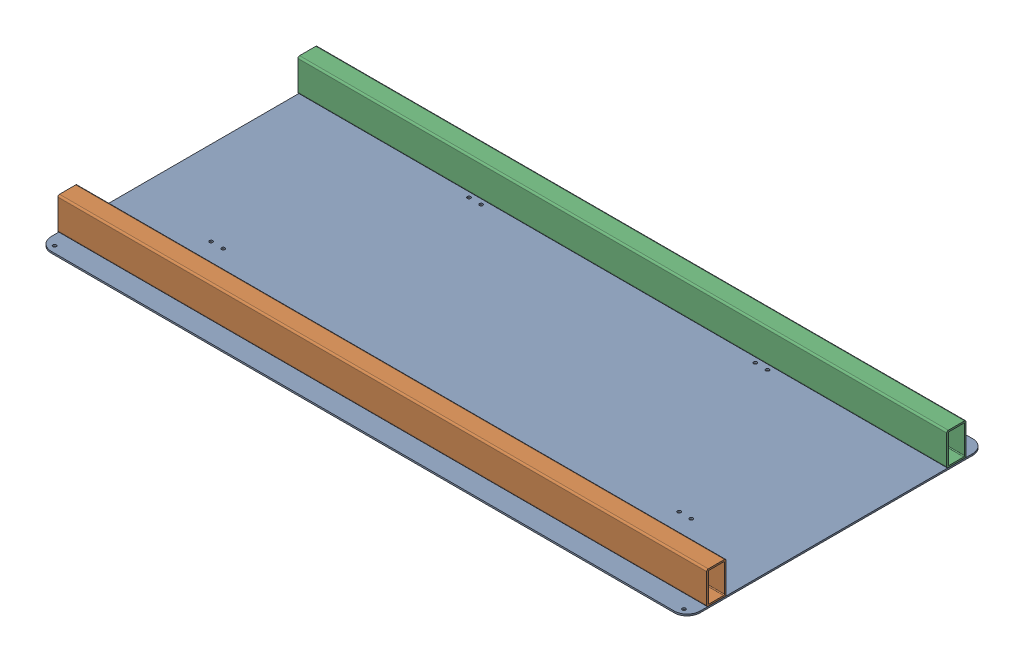
SolidWorks assembly GE-16076_ASM, configuration Default. Lengths in mm.
Overall size (1270 66.67 584.2).
3 component instances, 2 part files, 0 mates.
Components (placement in the parent):
- GE-16016-1: GE-16016 [Default] at origin size (1270 3.17 584.2)
- GE-16076-01-1: GE-16076-01 [Default] at (0 34.925 234.95) size (1270 63.5 38.1)
- GE-16076-01-2: GE-16076-01 [Default] at (0 34.925 -234.95) size (1270 63.5 38.1)
